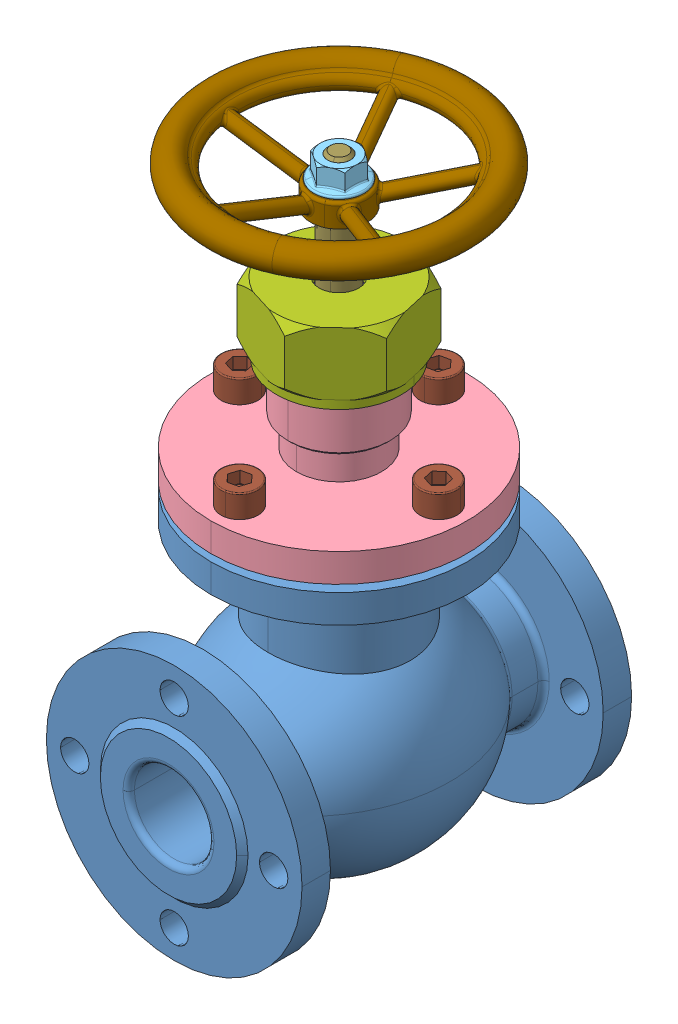
SolidWorks assembly Robinet, configuration Default. Lengths in mm.
Overall size (124.29 219 124.29).
19 component instances, 13 part files, 33 mates.
Components (placement in the parent):
- corp.step-1: corp.step [Default] at (44.4208 47.2241 94.2757) size (90 115 120)
- garnitura.step-1: garnitura.step [Default] at (44.4208 162.2241 94.2757) x (0.993584 0 -0.113101) z (0.113101 0 0.993584) size (22 2.5 22)
- garnitura1.step-1: garnitura1.step [Default] at (44.4208 114.2241 94.2757) size (40 2.5 40)
- ghidaj.step-1: ghidaj.step [Default] at (44.4208 104.7241 94.2757) size (90 65 90)
- Hex Flange Nut_AM.step-1: Hex Flange Nut_AM.step [Default] at (44.4208 219.2241 94.2757) x (0.553954 0 -0.832547) z (0 1 0) size (17.9 17.9 8)
- piesa_fixare.step-1: piesa_fixare.step [Default] at (44.4208 59.2241 94.2757) size (22 10 22)
- piulita_olandeza.step-1: piulita_olandeza.step [Default] at (44.4208 181.7241 94.2757) x (-0.222041 0 -0.975037) z (-0.975037 0 0.222041) size (50.81 25 49.9)
- presgarnitura.step-1: presgarnitura.step [Default] at (44.4208 164.7241 94.2757) x (0.990368 0 0.138458) z (-0.138458 0 0.990368) size (26 13 26)
- roata_actionare.step-1: roata_actionare.step [Default] at (44.4208 204.8521 94.2757) x (0.911956 0 -0.410289) z (0.410289 0 0.911956) size (94 18 94)
- scaun_ventil.step-1: scaun_ventil.step [Default] at (44.4208 42.9835 94.2757) size (22 10 22)
- Surub-locas-hex.step-1: Surub-locas-hex.step [Default] at (79.4208 137.7241 94.2757) x (0 -1 0) z (-0.976807 0 0.21412) size (33 13 13)
- tija.step-1: tija.step [Default] at (44.4208 88.2241 94.2757) x (0.911956 0 -0.410289) z (0.410289 0 0.911956) size (16 164 16)
- ventil.step-1: ventil.step [Default] at (44.4208 56.2241 94.2757) x (0.993267 0 -0.115845) z (0.115845 0 0.993267) size (24 20 24)
- garnitura.step-3: garnitura.step [Default] at (44.4208 159.7241 94.2757) x (0.989152 0 0.146898) z (-0.146898 0 0.989152) size (22 2.5 22)
- garnitura.step-4: garnitura.step [Default] at (44.4208 157.2241 94.2757) x (0.986181 0 0.165672) z (-0.165672 0 0.986181) size (22 2.5 22)
- garnitura.step-5: garnitura.step [Default] at (44.4208 154.7241 94.2757) x (0.999995 0 -0.003104) z (0.003104 0 0.999995) size (22 2.5 22)
- Surub-locas-hex.step-2: Surub-locas-hex.step [Default] at (44.4208 137.7241 129.2757) x (0 -1 0) z (-0.21412 0 -0.976807) size (33 13 13)
- Surub-locas-hex.step-3: Surub-locas-hex.step [Default] at (9.4208 137.7241 94.2757) x (0 -1 0) z (0.976807 0 -0.21412) size (33 13 13)
- Surub-locas-hex.step-4: Surub-locas-hex.step [Default] at (44.4208 137.7241 59.2757) x (0 -1 0) z (0.21412 0 0.976807) size (33 13 13)
Mates (geometry in assembly coordinates):
- Coincident3: coincident aligned: line of corp.step-1 through (44.4208 50.2241 94.2757) axis (0 -1 0); line of scaun_ventil.step-1 through (44.4208 52.2241 94.2757) axis (0 -1 0)
- Coincident4: coincident anti-aligned: circle of corp.step-1; circle of scaun_ventil.step-1
- Coincident5: coincident aligned: line of corp.step-1 through (44.4208 50.2241 94.2757) axis (0 -1 0); line of ventil.step-1 through (44.4208 67.2241 94.2757) axis (0 -1 0)
- Coincident6: coincident aligned: cone of scaun_ventil.step-1 through (44.4208 52.2241 94.2757) axis (0 -1 0); cone of ventil.step-1 through (44.4208 55.2241 94.2757) axis (0 -1 0)
- Coincident7: coincident aligned: line of corp.step-1 through (44.4208 117.2241 94.2757) axis (0 -1 0); line of tija.step-1 through (44.4208 131.2241 94.2757) axis (0 -1 0)
- Coincident8: coincident anti-aligned: plane of tija.step-1 through (44.4208 56.2241 94.2757) normal (0 -1 0); plane of ventil.step-1 through (44.4208 56.2241 94.2757) normal (0 1 0)
- Coincident9: coincident: line of assembly; axis of piesa_fixare.step-1 through (44.4208 70.254 94.2757) axis (0 -1 0); axis of tija.step-1 through (44.4208 58.2241 94.2757) axis (0 1 0)
- Coincident10: coincident anti-aligned: plane of piesa_fixare.step-1 through (44.4208 67.2241 94.2757) normal (0 -1 0); plane of ventil.step-1 through (45.4634 67.2241 103.2152) normal (0 1 0)
- Coincident11: coincident anti-aligned: line of garnitura1.step-1 through (44.4208 116.7241 94.2757) axis (0 -1 0); line of tija.step-1 through (44.4208 58.2241 94.2757) axis (0 1 0)
- Coincident12: coincident anti-aligned: plane of corp.step-1 through (44.4208 114.2241 109.2757) normal (0 1 0); plane of garnitura1.step-1 through (44.4208 114.2241 94.2757) normal (0 -1 0)
- Coincident13: coincident aligned: line of corp.step-1 through (44.4208 107.2241 129.2757) axis (0 1 0); line of ghidaj.step-1 through (44.4208 119.7241 129.2757) axis (0 1 0)
- Coincident14: coincident anti-aligned: plane of garnitura1.step-1 through (44.4208 116.7241 94.2757) normal (0 1 0); plane of ghidaj.step-1 through (44.4208 116.7241 94.2757) normal (0 -1 0)
- Concentric1: concentric aligned: cylinder of corp.step-1 through (44.4208 117.2241 129.2757) axis (0 1 0) radius 3.4; cylinder of ghidaj.step-1 through (44.4208 119.7241 129.2757) axis (0 1 0) radius 5
- Coincident15: coincident aligned: line of ghidaj.step-1 through (44.4208 119.7241 59.2757) axis (0 1 0); line of corp.step-1 through (44.4208 107.2241 59.2757) axis (0 1 0)
- Coincident17: coincident aligned: line of tija.step-1 through (44.4208 203.2241 94.2757) axis (0 -1 0); line of garnitura.step-5 through (44.4208 157.2241 94.2757) axis (0 -1 0)
- Coincident18: coincident anti-aligned: plane of ghidaj.step-1 through (44.4208 154.7241 94.2757) normal (0 1 0); plane of garnitura.step-5 through (44.4208 154.7241 94.2757) normal (0 -1 0)
- Coincident19: coincident aligned: line of tija.step-1 through (44.4208 203.2241 94.2757) axis (0 -1 0); line of garnitura.step-4 through (44.4208 159.7241 94.2757) axis (0 -1 0)
- Coincident20: coincident anti-aligned: plane of garnitura.step-4 through (44.4208 157.2241 94.2757) normal (0 -1 0); plane of garnitura.step-5 through (44.4208 157.2241 94.2757) normal (0 1 0)
- Coincident21: coincident aligned: line of tija.step-1 through (44.4208 203.2241 94.2757) axis (0 -1 0); line of garnitura.step-3 through (44.4208 162.2241 94.2757) axis (0 -1 0)
- Coincident22: coincident anti-aligned: plane of garnitura.step-3 through (44.4208 159.7241 94.2757) normal (0 -1 0); plane of garnitura.step-4 through (44.4208 159.7241 94.2757) normal (0 1 0)
- Coincident23: coincident aligned: line of garnitura.step-1 through (44.4208 164.7241 94.2757) axis (0 -1 0); line of tija.step-1 through (44.4208 203.2241 94.2757) axis (0 -1 0)
- Coincident24: coincident anti-aligned: plane of garnitura.step-1 through (44.4208 162.2241 94.2757) normal (0 -1 0); plane of garnitura.step-3 through (44.4208 162.2241 94.2757) normal (0 1 0)
- Coincident25: coincident: line of assembly; axis of piulita_olandeza.step-1 through (44.4208 185.2306 94.2757) axis (0 -1 0); axis of tija.step-1 through (44.4208 203.2241 94.2757) axis (0 -1 0)
- Coincident27: coincident aligned: line of presgarnitura.step-1 through (44.4208 177.7241 94.2757) axis (0 -1 0); line of tija.step-1 through (44.4208 203.2241 94.2757) axis (0 -1 0)
- Coincident28: coincident anti-aligned: plane of garnitura.step-1 through (44.4208 164.7241 94.2757) normal (0 1 0); plane of presgarnitura.step-1 through (44.4208 164.7241 94.2757) normal (0 -1 0)
- Coincident29: coincident anti-aligned: plane of piulita_olandeza.step-1 through (47.9734 177.7241 109.8763) normal (0 -1 0); plane of presgarnitura.step-1 through (44.4208 177.7241 94.2757) normal (0 1 0)
- Coincident30: coincident: line of assembly; axis of roata_actionare.step-1 through (44.4208 198.1212 94.2757) axis (0 1 0); axis of tija.step-1 through (44.4208 203.2241 94.2757) axis (0 -1 0)
- Coincident39: coincident anti-aligned: plane of roata_actionare.step-1 through (42.4141 201.2241 99.5647) normal (-0.410289 0 -0.911956); plane of tija.step-1 through (33.8951 203.2241 103.3974) normal (0.410289 0 0.911956)
- Coincident40: coincident anti-aligned: plane of roata_actionare.step-1 through (44.4208 203.2241 94.2757) normal (0 -1 0); plane of tija.step-1 through (32.254 203.2241 99.7496) normal (0 1 0)
- Coincident42: coincident aligned: line of Hex Flange Nut_AM.step-1 through (44.4208 208.6003 94.2757) axis (0 1 0); line of roata_actionare.step-1 through (44.4208 198.1212 94.2757) axis (0 1 0)
- Coincident43: coincident anti-aligned: plane of Hex Flange Nut_AM.step-1 through (38.172 211.2241 90.118) normal (0 -1 0); plane of roata_actionare.step-1 through (53.5403 211.2241 90.1729) normal (0 1 0)
- Coincident44: coincident aligned: line of ghidaj.step-1 through (79.4208 119.7241 94.2757) axis (0 1 0); line of Surub-locas-hex.step-1 through (79.4208 134.4161 94.2757) axis (0 1 0)
- Coincident45: coincident anti-aligned: plane of ghidaj.step-1 through (44.4208 129.7241 94.2757) normal (0 1 0); plane of Surub-locas-hex.step-1 through (80.8126 129.7241 100.625) normal (0 -1 0)
